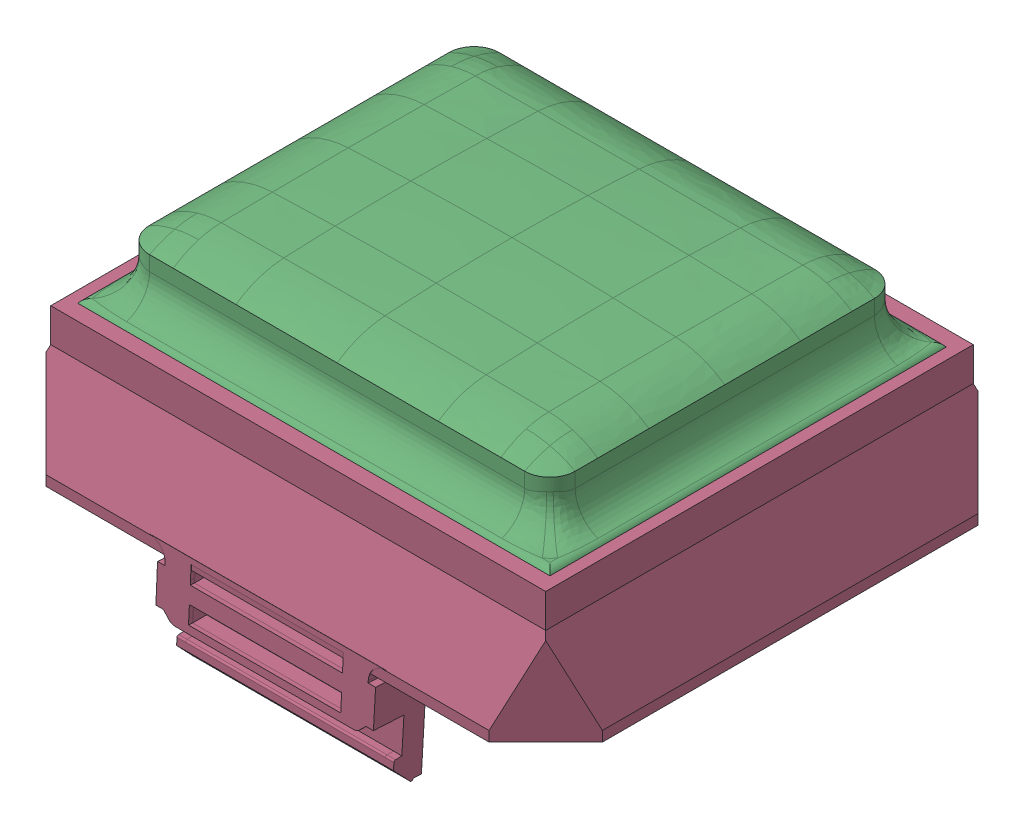
SolidWorks assembly ChessDesign, configuration 默认. Lengths in mm.
Overall size (33 18.27 29.5).
5 component instances, 5 part files, 13 mates.
Components (placement in the parent):
- Lens-1: Lens [默认] at origin size (28.33 2.18 23.83)
- InsideSkin-1: InsideSkin [默认] at (0.0001 0 0.2499) size (23.8 5.48 19.29)
- Topskin-1: Topskin [默认] at (0.0001 2 0.2499) size (28.02 6.25 23.52)
- Supportbase-2: Supportbase [默认] at origin size (33 14.02 29.5)
- ChessboardMarker-1: ChessboardMarker [默认] at (-4.7946 24.2 -14.5409) x (1 0 0) z (0 -1 0) size (22.6 16.44 0.67)
Mates (geometry in assembly coordinates):
- 同心2: concentric anti-aligned: cylinder of InsideSkin-1 through (10.8751 17.7531 8.6249) axis (0 1 0) radius 0.7; cylinder of Board3Con1612611OriginalSkin_TOP-1 through (10.8751 24 8.6249) axis (0 -1 0) radius 0.7
- 同心3: concentric anti-aligned: cylinder of InsideSkin-1 through (10.8751 17.7531 -9.1251) axis (0 1 0) radius 0.7; cylinder of Board3Con1612611OriginalSkin_TOP-1 through (10.8751 24 -9.1251) axis (0 -1 0) radius 0.7
- 重合4: coincident aligned: plane of InsideSkin-1 through (10.8751 19 -9.1251) normal (0 -1 0); plane of Board3Con1612611OriginalSkin_TOP-1 through (0.0001 19 0.2499) normal (0 -1 0)
- 重合6: coordinate: point of NewContiSupportBase-2
- 重合7: coincident anti-aligned: plane of lensall-1 through (13.75 19 -11.5) normal (0.939693 0.34202 0); plane of NewContiSupportBase-2 through (13.75 19 12.7803) normal (-0.939693 -0.34202 0)
- 同心5: concentric aligned: cylinder of lensall-1 through (13.3294 18.6938 -11.0794) axis (-0.323616 0.889126 0.323616) radius 0.5; cylinder of NewContiSupportBase-2 through (10.7866 25.6801 -8.5366) axis (-0.323616 0.889126 0.323616) radius 0.5
- 重合8: coincident anti-aligned: plane of lensall-1 through (0 18 0) normal (0 -1 0); plane of NewContiSupportBase-2 through (0 18 0) normal (0 1 0)
- 重合9: coincident anti-aligned: plane of lensall-1 through (0 19 0) normal (0 1 0); plane of Board3Con1612611OriginalSkin_TOP-1 through (0.0001 19 0.2499) normal (0 -1 0)
- 重合10: coincident anti-aligned: plane of Board3Con1612611OriginalSkin_TOP-1 through (0.0001 19 11.7499) normal (0 0 1); plane of NewContiSupportBase-2 through (-13.5999 21 11.7499) normal (0 0 -1)
- 重合11: coincident anti-aligned: plane of Board3Con1612611OriginalSkin_TOP-1 through (14.0001 19 0.2499) normal (1 0 0); plane of NewContiSupportBase-2 through (14.0001 21 11.7499) normal (-1 0 0)
- 宽度1: width aligned: plane of InsideSkin-1 through (-11.3749 17.7531 9.3249) normal (0 0 1); plane of ChessboardMarker-1 through (-11.3749 17.7531 -9.8251) normal (0 0 -1); plane of InsideSkin-1 through (2.8501 23.8 7.9249) normal (0 0 1); plane of ChessboardMarker-1 through (0.8001 23.8 -8.4251) normal (0 0 -1)
- 宽度2: width aligned: plane of InsideSkin-1 through (11.5751 17.7531 -9.1251) normal (1 0 0); plane of ChessboardMarker-1 through (-12.0749 17.7531 -9.1251) normal (-1 0 0); plane of InsideSkin-1 through (11.0001 23.8 -6.4251) normal (1 0 0); plane of ChessboardMarker-1 through (-11.4999 23.8 -6.4251) normal (-1 0 0)
- 距离1: distance = 4.8 mm anti-aligned: plane of Lens-1 through (0 19 0) normal (0 1 0); plane of ChessboardMarker-1 through (-4.7946 23.8 -10.4409) normal (0 -1 0)
